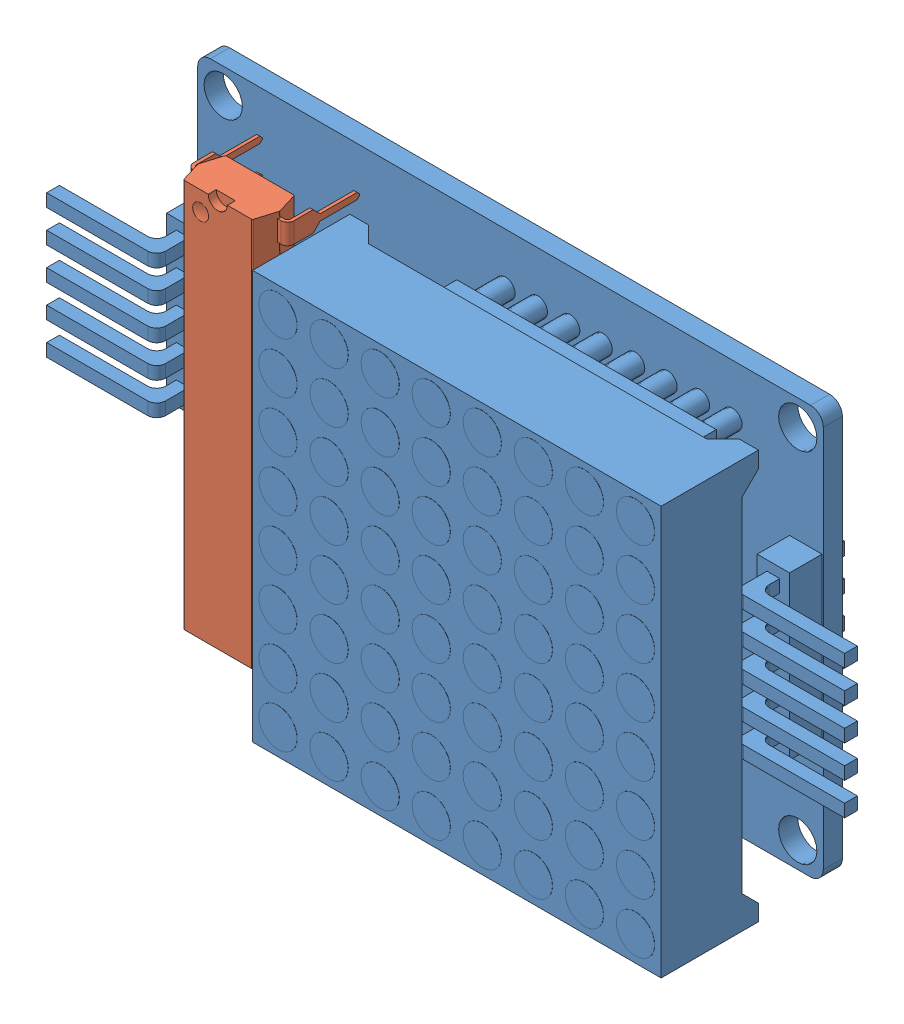
SolidWorks assembly MatrizLEDs8x8, configuration Predeterminado. Lengths in mm.
Overall size (62.5 32 15.25).
3 component instances, 3 part files, 5 mates.
Components (placement in the parent):
- max7219_board-1: max7219_board [Predeterminado] at (-7.8953 -3.0915 62.5) size (62.5 32 15.25)
- IC_Sockel_24P-1: IC_Sockel_24P [Predeterminado] at (-22.3557 12.1485 64.5) x (-1 0 0) z (0 1 0) (suppressed, hidden)
- DIP24-1: DIP24 [Predeterminado] at (-25.0557 12.0985 69.16) x (-1 0 0) z (0 1 0) size (7.87 7.17 30.48)
Mates (geometry in assembly coordinates):
- Distancia1: distance = 0.5 mm: plane of IC_Sockel_24P-1 through (-27.4357 12.1485 64.5) normal (0 0 -1); plane of max7219_board-1 through (-31.3953 -18.0915 64) normal (0 0 1)
- Distancia2: distance = 0.76 mm: plane of IC_Sockel_24P-1 through (-24.8957 12.1485 67.08) normal (0 1 0); plane of max7219_board-1 through (-31.3953 12.9085 64) normal (0 1 0)
- Coincidente4: coincident: plane of IC_Sockel_24P-1 through (-18.4207 -17.8115 69.66) normal (-1 0 0); plane of DIP24-1 through (-18.4207 10.8285 70.81) normal (1 0 0)
- Coincidente5: coincident: plane of IC_Sockel_24P-1 through (-18.4207 11.6285 69.66) normal (0 -1 0); plane of DIP24-1 through (-19.6557 11.6285 70.935) normal (0 1 0)
- Distancia4: distance = 0.5 mm: plane of DIP24-1 through (-25.0557 12.0985 69.16) normal (0 0 -1); plane of IC_Sockel_24P-1 through (-22.3557 -3.0915 68.66) normal (0 0 1)
